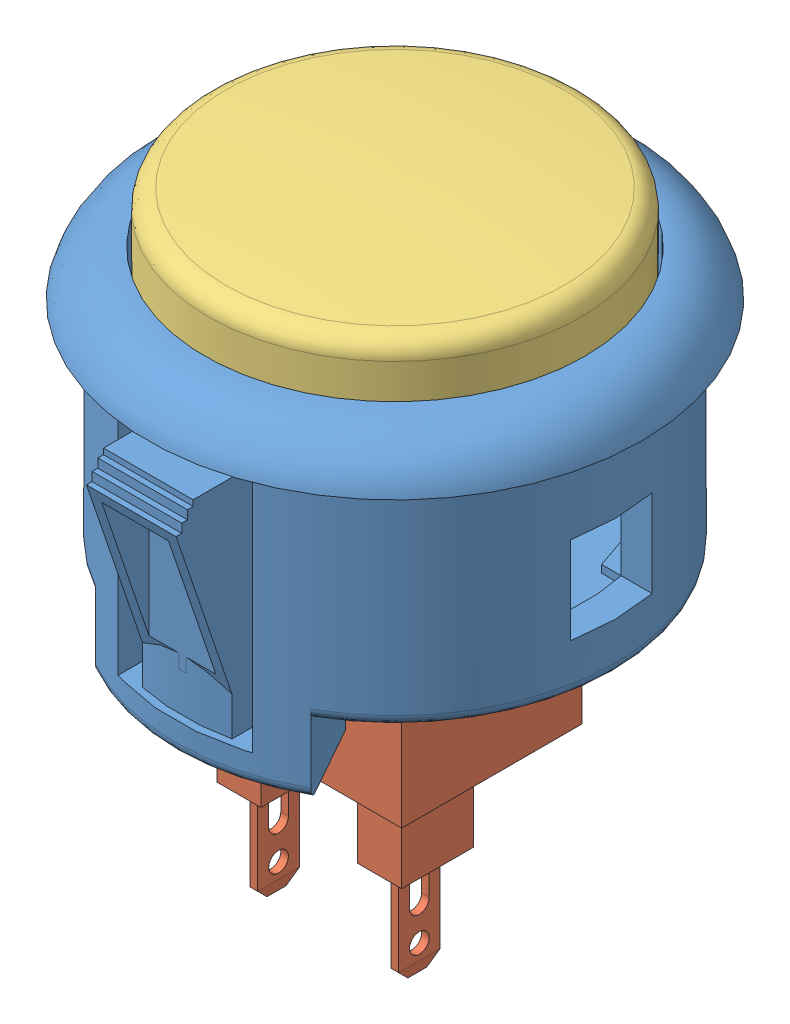
SolidWorks assembly !sanwa_button, configuration Default. Lengths in mm.
Overall size (33.02 41.99 35.3).
3 component instances, 3 part files, 6 mates.
Components (placement in the parent):
- base-1: base [Default] at (-11.8549 15.7525 1.5934) size (33.02 22.1 35.3)
- microswitch-1: microswitch [Default] at (-11.8549 -8.6795 1.5934) x (1 0 0) z (0 1 0) size (15.01 12.07 29.85)
- top_cap-1: top_cap [Default] at (-11.8549 16.7258 1.5934) size (26.67 15.14 24.94)
Mates (geometry in assembly coordinates):
- Coincident1: coincident anti-aligned: plane of microswitch-1 through (-11.8549 2.4965 16.7147) normal (0 -1 0); plane of base-1 through (-3.1554 2.4965 1.5934) normal (0 1 0)
- Coincident2: coincident anti-aligned: plane of base-1 through (-5.3779 18.7535 7.6259) normal (-1 0 0); plane of microswitch-1 through (-5.3779 4.0205 -4.4391) normal (1 0 0)
- Coincident3: coincident anti-aligned: plane of base-1 through (-5.3779 18.7535 7.6259) normal (0 0 -1); plane of microswitch-1 through (-18.3319 4.0205 7.6259) normal (0 0 1)
- Concentric1: concentric anti-aligned: cylinder of base-1 through (-11.8549 18.7525 1.5934) axis (0 1 0) radius 12.7; cylinder of top_cap-1 through (-11.8549 16.7258 1.5934) axis (0 -1 0) radius 12.4714
- Parallel1: parallel aligned: plane of microswitch-1 through (-12.6169 10.6245 4.6033) normal (-1 0 0); plane of top_cap-1 through (-10.9659 27.1099 -1.4927) normal (-1 0 0)
- LimitDistance1: limit distance = 3.6068 mm anti-aligned: plane of top_cap-1 through (-3.8224 7.6273 1.5934) normal (0 -1 0); plane of microswitch-1 through (-18.3319 4.0205 7.6259) normal (0 1 0)
